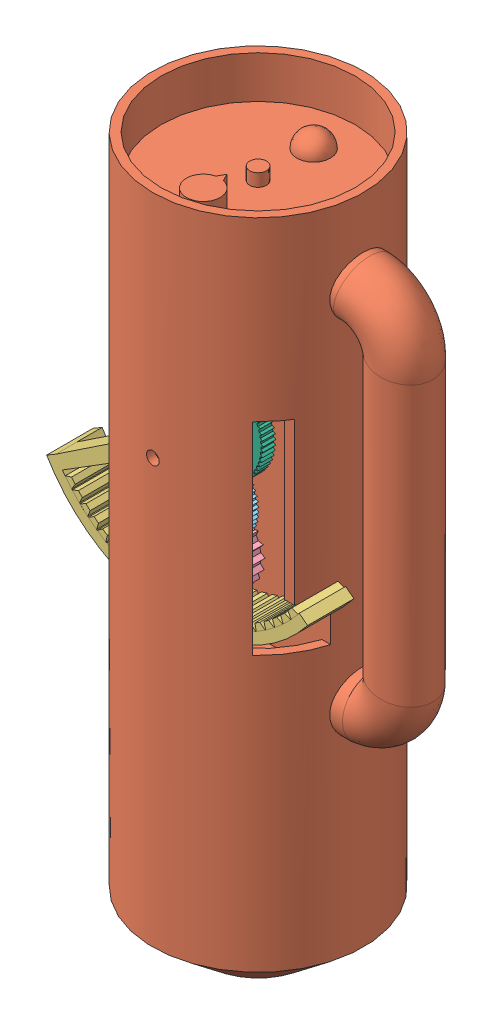
SolidWorks assembly Water_pen_assembly, configuration Default. Lengths in mm.
Overall size (76.8 165.13 50).
6 component instances, 6 part files, 14 mates.
Components (placement in the parent):
- gear4_near_hand_crank-1: gear4_near_hand_crank [Default] at (14.0631 51.1437 144.8792) x (0.986262 -0.16519 0) z (0 0 1) size (24.14 24.14 6)
- 3-D  model-2: 3-D  model [Default] at (24.6683 -0.0383 106.0756) x (-1 0 0) z (0 0 1) size (67.37 165.13 50)
- hand_Crank-1: hand_Crank [Default] at (19.355 142.4783 92.9379) x (0.992154 0.125019 0) z (0 0 -1) size (60.91 39.5 11)
- gear1_near_hand_crank-1: gear1_near_hand_crank [Default] at (-16.926 128.8094 86.9379) x (0.792489 0.609887 0) z (0 0 -1) size (16.98 17 6)
- gear2_near_hand_crank-1: gear2_near_hand_crank [Default] at (22.1928 153.2154 144.8792) x (-0.999301 -0.037394 0) z (0 0 1) size (20.14 20.14 6)
- gear3_near_hand_crank-1: gear3_near_hand_crank [Default] at (-3.8651 41.6868 86.9379) x (-0.899155 0.437629 0) z (0 0 -1) size (22.14 22.14 6)
Mates (geometry in assembly coordinates):
- Coincident2: coincident anti-aligned: plane of 3-D  model-2 through (24.6683 57.9617 112.9086) normal (0 0 1); plane of gear1_near_hand_crank-1 through (-16.926 128.8094 112.9086) normal (0 0 -1)
- Concentric2: concentric aligned: cylinder of 3-D  model-2 through (24.6683 74.7617 111.4086) axis (0 0 1) radius 0.5; cylinder of gear1_near_hand_crank-1 through (24.6683 74.7617 112.9086) axis (0 0 1) radius 0.5
- Coincident3: coincident anti-aligned: plane of 3-D  model-2 through (24.6683 57.9617 112.9086) normal (0 0 1); plane of gear2_near_hand_crank-1 through (24.6683 87.0617 112.9086) normal (0 0 -1)
- Concentric3: concentric anti-aligned: cylinder of 3-D  model-2 through (24.6683 87.0617 111.4086) axis (0 0 1) radius 0.5; cylinder of gear2_near_hand_crank-1 through (24.6683 87.0617 118.9086) axis (0 0 -1) radius 0.5
- Coincident4: coincident anti-aligned: plane of 3-D  model-2 through (24.6683 57.9617 112.9086) normal (0 0 1); plane of gear3_near_hand_crank-1 through (-3.8651 41.6868 112.9086) normal (0 0 -1)
- Concentric4: concentric aligned: cylinder of 3-D  model-2 through (24.6683 100.3117 111.4086) axis (0 0 1) radius 0.5; cylinder of gear3_near_hand_crank-1 through (24.6683 100.3117 112.9086) axis (0 0 1) radius 0.5
- Coincident5: coincident anti-aligned: plane of gear4_near_hand_crank-1 through (24.6683 114.4617 112.9086) normal (0 0 -1); plane of 3-D  model-2 through (24.6683 57.9617 112.9086) normal (0 0 1)
- Concentric5: concentric anti-aligned: cylinder of gear4_near_hand_crank-1 through (24.6683 114.4617 118.9086) axis (0 0 -1) radius 0.5; cylinder of 3-D  model-2 through (24.6683 114.4617 111.4086) axis (0 0 1) radius 0.5
- Concentric7: concentric anti-aligned: cylinder of hand_Crank-1 through (24.6683 100.3117 123.9086) axis (0 0 -1) radius 1.5; cylinder of gear3_near_hand_crank-1 through (24.6683 100.3117 112.9086) axis (0 0 1) radius 0.5
- Coincident7: coincident anti-aligned: plane of hand_Crank-1 through (19.355 142.4783 118.9086) normal (0 0 -1); plane of gear3_near_hand_crank-1 through (24.6683 100.3117 118.9086) normal (0 0 1)
- GearMate1: gear = 1 : 1 mm: line of gear1_near_hand_crank-1 through (31.9186 70.2251 115.9086) axis (0 0 -1); line of hand_Crank-1 through (49.5922 77.9507 123.9086) axis (0.475019 -0.879975 0)
- GearMate2: gear = 1 : 1 mm: line of gear1_near_hand_crank-1 through (23.0826 76.8222 115.9086) axis (0 0 1); line of gear2_near_hand_crank-1 through (31.9367 80.0799 115.9086) axis (0 0 1)
- GearMate3: gear = 1 : 1 mm: line of gear2_near_hand_crank-1 through (25.3689 89.5639 112.9086) axis (0.185805 -0.982587 0); line of gear3_near_hand_crank-1 through (21.6224 89.6627 112.9086) axis (-0.185805 0.982587 0)
- GearMate4: gear = 1 : 1 mm: line of gear4_near_hand_crank-1 through (22.8085 103.1131 118.9086) axis (0.319163 -0.9477 0); line of gear3_near_hand_crank-1 through (25.2081 102.2375 118.9086) axis (-0.319163 0.9477 0)
